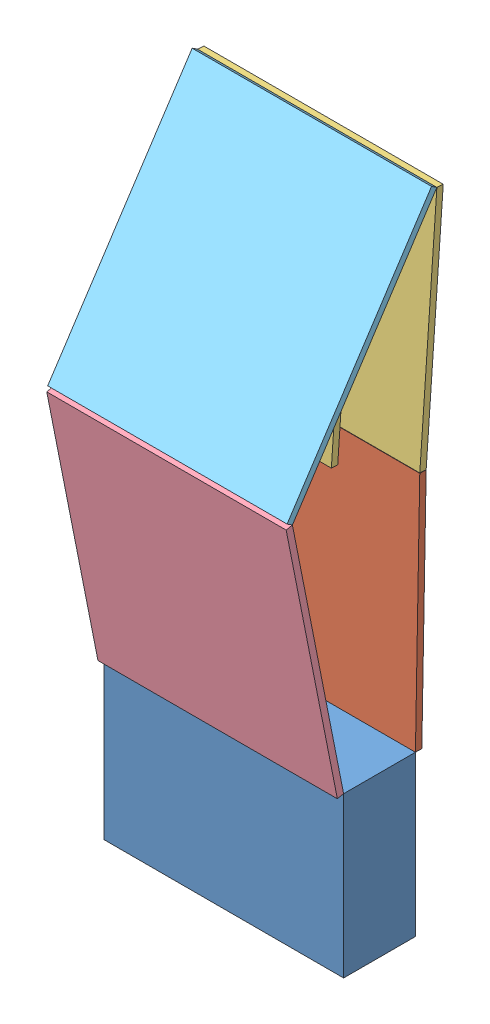
SolidWorks assembly Wing Assembly, configuration Default. Lengths in mm.
Overall size (150 402 98.43).
5 component instances, 5 part files, 9 mates.
Components (placement in the parent):
- E-1: E [Default] at (-40.975 121.9149 202.6142) size (150 100 45)
- A-1: A [Default] at (-40.975 221.8424 153.6148) x (1 0 0) z (0 -0.999836 0.018123) size (150 4 150)
- B-1: B [Default] at (-40.975 371.8178 150.8964) x (1 0 0) z (0 -0.997449 0.071384) size (150 8 170)
- C-1: C [Default] at (-40.975 383.7658 234.6965) x (0 -0.980915 -0.194438) z (-1 0 0) size (165 4 150)
- D-1: D [Default] at (-40.975 383.7658 234.6965) x (1 0 0) z (0 -0.83609 0.548593) size (150 4 165)
Mates (geometry in assembly coordinates):
- Coincident1: coincident anti-aligned: line of E-1 through (109.025 221.9149 157.6142) axis (-1 0 0); line of A-1 through (-40.975 221.9149 157.6142) axis (1 0 0)
- Coincident2: coincident aligned: plane of E-1 through (109.025 221.9149 202.6142) normal (1 0 0); plane of A-1 through (109.025 221.9149 157.6142) normal (1 0 0)
- Coincident4: coincident aligned: plane of A-1 through (109.025 221.9149 157.6142) normal (1 0 0); plane of B-1 through (109.025 372.1033 154.8862) normal (1 0 0)
- Coincident8: coincident aligned: plane of E-1 through (109.025 221.9149 202.6142) normal (1 0 0); plane of D-1 through (109.025 385.9602 238.0409) normal (1 0 0)
- Coincident9: coincident aligned: line of B-1 through (109.025 521.7206 144.1787) axis (-1 0 0); line of D-1 through (109.025 521.7206 144.1787) axis (-1 0 0)
- Coincident10: coincident anti-aligned: line of A-1 through (109.025 371.8178 150.8964) axis (-1 0 0); line of B-1 through (-40.975 371.8178 150.8964) axis (1 0 0)
- Coincident11: coincident aligned: line of E-1 through (-40.975 221.9149 202.6142) axis (1 0 0); line of C-1 through (-40.975 221.9149 202.6142) axis (1 0 0)
- Coincident12: coincident aligned: plane of E-1 through (109.025 221.9149 202.6142) normal (1 0 0); plane of C-1 through (109.025 382.9881 238.6202) normal (1 0 0)
- Coincident13: coincident anti-aligned: line of C-1 through (109.025 383.7658 234.6965) axis (-1 0 0); line of D-1 through (-40.975 383.7658 234.6965) axis (1 0 0)
